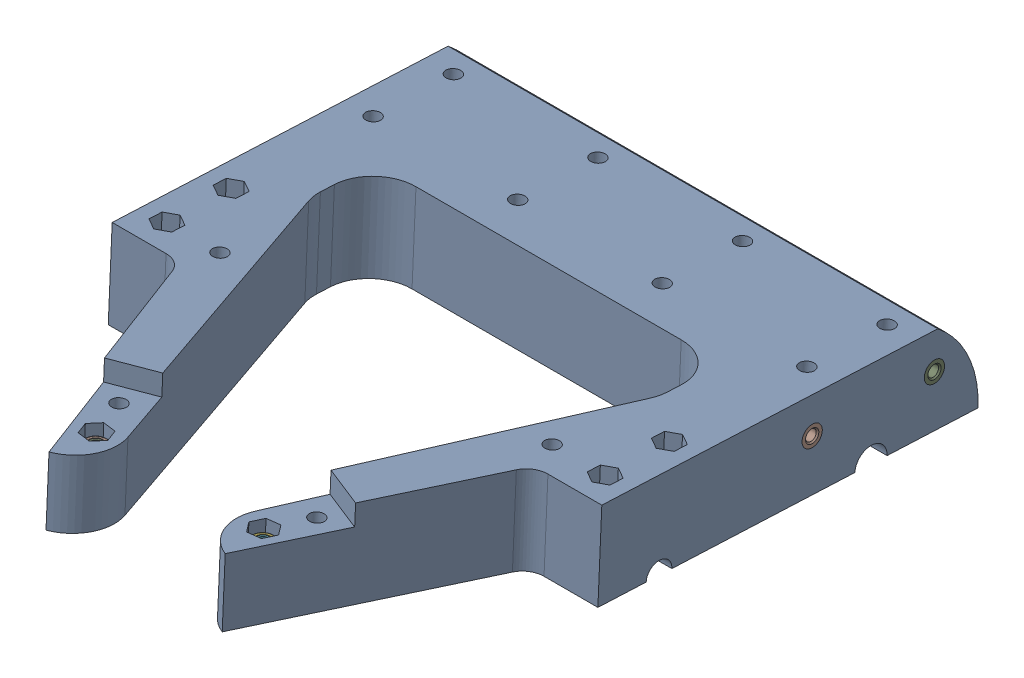
SolidWorks assembly Main Casing B Pre-Asmbly, configuration Default. Lengths in mm.
Overall size (152.4 35.57 187.69).
29 component instances, 4 part files, 0 mates.
Components (placement in the parent):
- Main Casing B-1: Main Casing B [Default] at (0 -139.7 43.8404) x (1 0 0) z (0 0.045363 0.998971) size (152.4 27.13 186.65)
- 93625A150-1: 93625A150 [Default] at (-30.8014 -124.8966 171.4366) x (0.927184 -0.016993 -0.374221) z (0 -0.998971 0.045363) size (7 8.08 5)
  - 93625A150_2-1: 93625A150_2 [Default] at origin size (7 8.08 5)
  - 93625A150-1: 93625A150 [Default] at origin size (6.53 6.53 0.53)
- 93625A150-2: 93625A150 [Default] at (30.8014 -124.8966 171.4366) x (0.927184 0.016993 0.374221) z (0 -0.998971 0.045363) size (7 8.08 5)
  - 93625A150_2-1: 93625A150_2 [Default] at origin size (7 8.08 5)
  - 93625A150-1: 93625A150 [Default] at origin size (6.53 6.53 0.53)
- 93625A150-3: 93625A150 [Default] at (26.018 -120.7292 183.0242) x (0.927184 0.016993 0.374221) z (0 0.998971 -0.045363) size (7 8.08 5)
  - 93625A150_2-1: 93625A150_2 [Default] at origin size (7 8.08 5)
  - 93625A150-1: 93625A150 [Default] at origin size (6.53 6.53 0.53)
- 93625A150-4: 93625A150 [Default] at (-26.018 -120.7292 183.0242) x (0.927184 -0.016993 -0.374221) z (0 0.998971 -0.045363) size (7 8.08 5)
  - 93625A150_2-1: 93625A150_2 [Default] at origin size (7 8.08 5)
  - 93625A150-1: 93625A150 [Default] at origin size (6.53 6.53 0.53)
- 93625A150-5: 93625A150 [Default] at (-68.2 -128.2463 119.4387) x (1 0 0) z (0 0.998971 -0.045363) size (7 8.08 5)
  - 93625A150_2-1: 93625A150_2 [Default] at origin size (7 8.08 5)
  - 93625A150-1: 93625A150 [Default] at origin size (6.53 6.53 0.53)
- 93625A150-6: 93625A150 [Default] at (-68.2 -129.1536 99.4592) x (1 0 0) z (0 0.998971 -0.045363) size (7 8.08 5)
  - 93625A150_2-1: 93625A150_2 [Default] at origin size (7 8.08 5)
  - 93625A150-1: 93625A150 [Default] at origin size (6.53 6.53 0.53)
- 93625A150-7: 93625A150 [Default] at (68.2 -128.2463 119.4387) x (1 0 0) z (0 0.998971 -0.045363) size (7 8.08 5)
  - 93625A150_2-1: 93625A150_2 [Default] at origin size (7 8.08 5)
  - 93625A150-1: 93625A150 [Default] at origin size (6.53 6.53 0.53)
- 93625A150-8: 93625A150 [Default] at (68.2 -129.1536 99.4592) x (1 0 0) z (0 0.998971 -0.045363) size (7 8.08 5)
  - 93625A150_2-1: 93625A150_2 [Default] at origin size (7 8.08 5)
  - 93625A150-1: 93625A150 [Default] at origin size (6.53 6.53 0.53)
- 94180A351-1: 94180A351 [Default] at (-76.2 -122.9772 62.1507) x (0 -0.045363 -0.998971) z (-1 0 0) size (6.35 6.35 4.7)
- 94180A351-2: 94180A351 [Default] at (-76.2 -124.7055 24.0899) x (0 -0.045363 -0.998971) z (-1 0 0) size (6.35 6.35 4.7)
- 94180A351-3: 94180A351 [Default] at (76.2 -122.9772 62.1507) x (0 0.045363 0.998971) z (1 0 0) size (6.35 6.35 4.7)
- 94180A351-4: 94180A351 [Default] at (76.2 -124.7055 24.0899) x (0 0.045363 0.998971) z (1 0 0) size (6.35 6.35 4.7)
